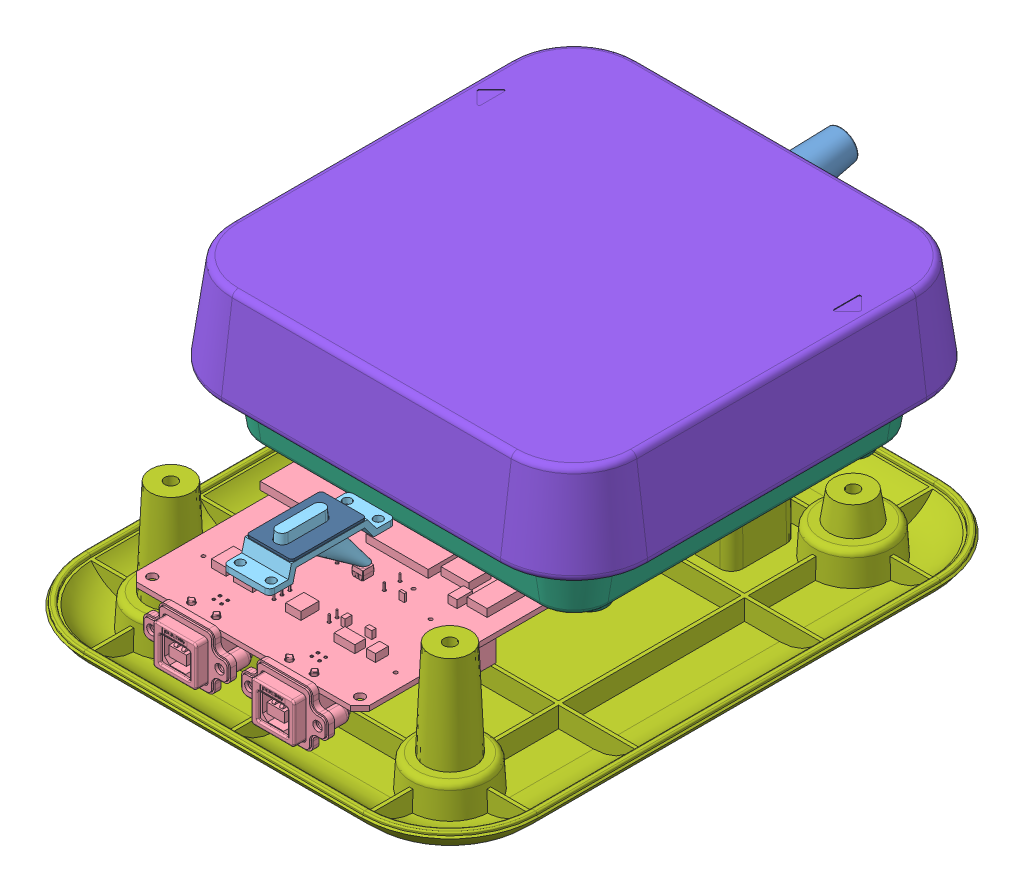
SolidWorks assembly FullComponentAssem, configuration Default. Lengths in mm.
Overall size (147.12 89.52 201.92).
15 component instances, 11 part files, 20 mates.
Components (placement in the parent):
- 690-13322-01-1: 690-13322-01 [main top] at origin size (149.92 47.5 189.92) (hidden)
- 690-13334-01-1: 690-13334-01 [Default] at (-0.0242 60.2538 -86.975) x (1 0 0) z (0 0.991228 0.132164) size (24 32.97 24)
- 690-13338-01-1: 690-13338-01 [Default] at (45 -11.523 65) size (20 13 20)
- 690-13338-01-2: 690-13338-01 [Default] at (-45 -11.523 -65) x (-0.269195 0 -0.963086) z (0.963086 0 -0.269195) size (20 13 20)
- 690-13338-01-3: 690-13338-01 [Default] at (-45 -11.523 65) size (20 13 20)
- 690-13338-01-4: 690-13338-01 [Default] at (45 -11.523 -65) size (20 13 20)
- LITEactivebreakoutboard02oct2018-1: LITEactivebreakoutboard02oct2018 [Default] at (37.4775 35.8263 24.9204) x (0 0 -1) z (0 1 0) size (93.5 74.96 48.9)
- LITEsingleboard27sep2018-1: LITEsingleboard27sep2018 [Default] at (37.4986 19.7595 86.5071) x (0 0 -1) z (0 1 0) size (161.48 77.75 25.95)
- new_690-13335-01-1: new_690-13335-01 [Default] at (0.0001 42 68.1254) x (-0.000003 0 -1) z (-1 0 0.000003) size (40.5 22.51 15)
- 690-13313-01-2: 690-13313-01 [adapter bottom] at origin size (131.73 26.72 131.73)
- 690-13321-01-2: 690-13321-01 [amp bottom] at origin size (147.12 44 187.12)
- 690-13320-01-2: 690-13320-01 [adapter top] at origin size (137.43 45 137.43)
- 690-13337-01-1: 690-13337-01 [Default] at (0.0103 23.5822 -50.7468) x (1 0 0) z (0 0 1) size (68 5.5 14.5)
- 690-13337-01-2: 690-13337-01 [Default] at (0.005 30.4278 -50.8207) x (-1 0 0) z (0 0 1) size (68 5.5 14.5)
- 690-13336-01-1: 690-13336-01 [Default] at (0.0273 42.762 68.0956) x (0 0 -1) z (-1 0 0) size (24.1 0.76 14.6)
Mates (geometry in assembly coordinates):
- Coincident11: coincident: plane of 690-13322-01-1 through (0 19.7595 0) normal (0 1 0); plane of LITEsingleboard27sep2018-1 through (37.4986 19.7595 86.5071) normal (0 1 0)
- Parallel7: parallel: plane of 690-13322-01-1 through (0 0 0) normal (0 0 1); plane of LITEsingleboard27sep2018-1 through (37.4986 19.7595 9.0056) normal (0 0 1)
- Coincident13: coincident: plane of 690-13334-01-1 through (-12.0242 60.1216 -85.9838) normal (0 -0.132164 0.991228); plane of 690-13320-01-2 through (0 48.2643 -87.5648) normal (0 0.132164 -0.991228)
- Coincident14: coincident: plane of LITEactivebreakoutboard02oct2018-1 through (37.4775 34.2405 24.9204) normal (0 -1 0); plane of 690-13313-01-2 through (-33.5 34.2405 -37) normal (0 1 0)
- Coincident15: coincident: plane of LITEactivebreakoutboard02oct2018-1; plane of 690-13313-01-2 through (0 0 0) normal (1 0 0)
- Distance1: distance = 21.8281 mm: plane of LITEactivebreakoutboard02oct2018-1 through (37.4775 35.8263 -21.8281) normal (0 0 1); plane of 690-13313-01-2 through (0 0 0) normal (0 0 1)
- Coincident17: coincident: cone of 690-13338-01-2 through (-45 -11.523 -65) axis (0 1 0); cone of 690-13321-01-2 through (-45 -12 -65) axis (0 1 0)
- Coincident18: coincident: cone of 690-13338-01-3 through (-45 -11.523 65) axis (0 1 0); cone of 690-13321-01-2 through (-45 -12 65) axis (0 1 0)
- Coincident19: coincident: cone of 690-13338-01-1 through (45 -11.523 65) axis (0 1 0); cone of 690-13321-01-2 through (45 -12 65) axis (0 1 0)
- Coincident20: coincident: cone of 690-13338-01-4 through (45 -11.523 -65) axis (0 1 0); cone of 690-13321-01-2 through (45 -12 -65) axis (0 1 0)
- Coincident21: coincident: plane of LITEsingleboard27sep2018-1 through (-0.0492 23.5822 -50.653) normal (0 1 0); plane of 690-13337-01-1 through (31.0288 23.5822 -46.4782) normal (0 -1 0)
- Coincident22: coincident: plane of LITEsingleboard27sep2018-1 through (-30.9737 23.5822 -45.4968) normal (0 0 1); plane of 690-13337-01-1 through (-31.0082 20.0822 -45.4968) normal (0 0 -1)
- Coincident23: coincident: plane of LITEactivebreakoutboard02oct2018-1 through (-0.04 30.4278 -50.7207) normal (0 -1 0); plane of 690-13337-01-2 through (-31.0135 30.4278 -46.5522) normal (0 1 0)
- Coincident24: coincident: plane of LITEactivebreakoutboard02oct2018-1 through (31.915 30.4278 -45.5707) normal (0 0 1); plane of 690-13337-01-2 through (31.0235 33.9278 -45.5707) normal (0 0 -1)
- Coincident25: coincident: plane of LITEactivebreakoutboard02oct2018-1 through (-31.995 30.4278 -45.5707) normal (-1 0 0); plane of 690-13337-01-2 through (-31.995 33.9278 -46.5522) normal (1 0 0)
- Coincident26: coincident: plane of LITEsingleboard27sep2018-1 through (-31.9897 23.5822 -54.7932) normal (-1 0 0); plane of 690-13337-01-1 through (-31.9897 20.0822 -55.0153) normal (1 0 0)
- Concentric1: concentric: cone of 690-13322-01-1 through (5 42 82.6254) axis (0 1 0); cone of new_690-13335-01-1 through (5.0001 38 82.6257) axis (0 -1 0)
- Coincident30: coincident: plane of 690-13322-01-1 through (0 38 0) normal (0 -1 0); plane of new_690-13335-01-1 through (-7.4999 38 79.6258) normal (0 1 0)
- Concentric2: concentric: cone of 690-13322-01-1 through (-5 42 48.125) axis (0 1 0); cone of new_690-13335-01-1 through (-5 38 48.125) axis (0 -1 0)
- Coincident34: coincident: plane of new_690-13335-01-1 through (-7.4999 42 76.1258) normal (0 1 0); plane of 690-13336-01-1 through (6.3273 42 55.296) normal (0 -1 0)
